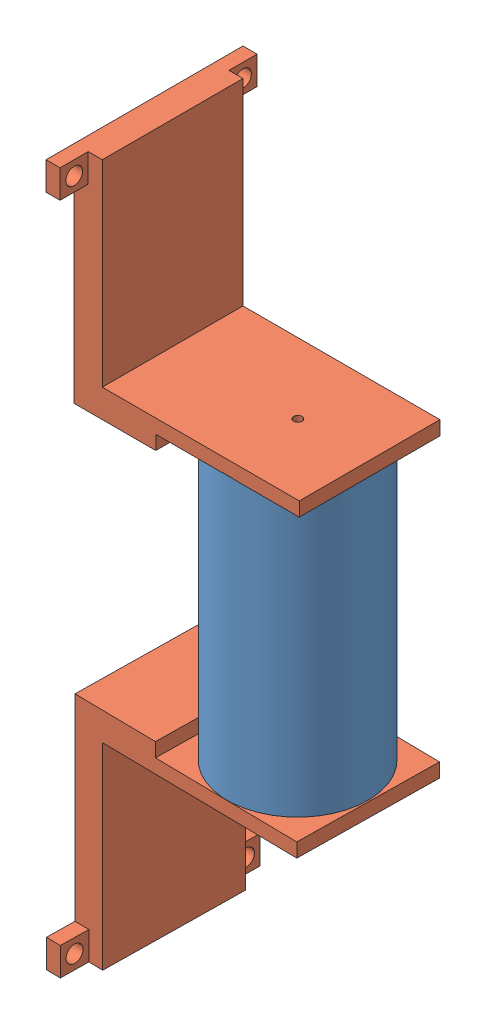
SolidWorks assembly Assem1, configuration Default. Lengths in mm.
Overall size (81.01 249.9 71.16).
3 component instances, 2 part files, 2 mates.
Components (placement in the parent):
- ostvane-3: ostvane [Default] at (97.6349 -41.7298 73.2117) size (50 100 50)
- hmun k miduni-1: hmun k miduni [Default] at (43.1444 106.926 62.9828) x (0 -1 0) z (0 0 1) size (80 80 70)
- hmun k miduni-2: hmun k miduni [Default] at (42.9917 -90.4898 82.6197) x (0 1 0) z (0.014602 0 -0.999893) size (80 80 70)
Mates (geometry in assembly coordinates):
- Angle1: planar angle = 0 rad: plane of hmun k miduni-1 through (43.1444 58.166 62.9828) normal (0 -1 0); plane of ostvane-3 through (97.6349 58.2702 73.2117) normal (0 1 0)
- Coincident5: coincident: plane of ostvane-3 through (97.6349 -41.7298 73.2117) normal (0 -1 0); plane of hmun k miduni-2 through (42.9917 -41.7298 82.6197) normal (0 1 0)
